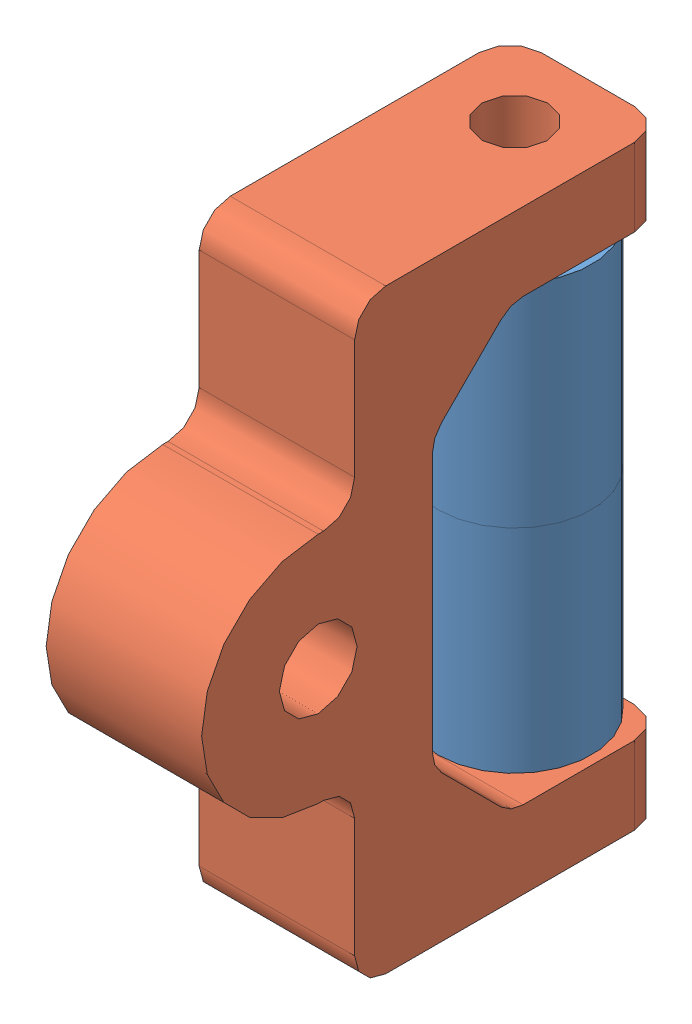
SolidWorks assembly Assem1, configuration Default. Lengths in mm.
Overall size (12.7 48.67 38.19).
3 component instances, 2 part files, 5 mates.
Components (placement in the parent):
- Nylon_Spacer-1: Nylon_Spacer [Default] at origin size (12.52 17.35 12.52)
- Nylon_Spacer-2: Nylon_Spacer [Default] at (0 17.3482 0) size (12.52 17.35 12.52)
- Nylon_Support-1: Nylon_Support [Default] at (6.35 -0.635 13.081) x (0 1 0) z (0 0 1) size (48.67 12.7 37.9)
Mates (geometry in assembly coordinates):
- Coincident1: coincident anti-aligned: plane of Nylon_Spacer-1 through (0 17.3482 0) normal (0 1 0); plane of Nylon_Spacer-2 through (0 17.3482 0) normal (0 -1 0)
- Concentric1: concentric aligned: circle of Nylon_Spacer-1; circle of Nylon_Spacer-2
- Parallel1: parallel anti-aligned: plane of Nylon_Spacer-2 through (0 34.6964 0) normal (0 1 0); plane of Nylon_Support-1 through (-6.35 35.3314 13.081) normal (0 -1 0)
- Width1: width anti-aligned: plane of Nylon_Support-1 through (-6.35 -0.635 13.081) normal (0 1 0); plane of Nylon_Support-1 through (-6.35 35.3314 13.081) normal (0 -1 0); plane of Nylon_Spacer-1 through (0 0 0) normal (0 -1 0); plane of Nylon_Spacer-2 through (0 34.6964 0) normal (0 1 0)
- Concentric2: concentric aligned: circle of Nylon_Spacer-2; circle of Nylon_Support-1
